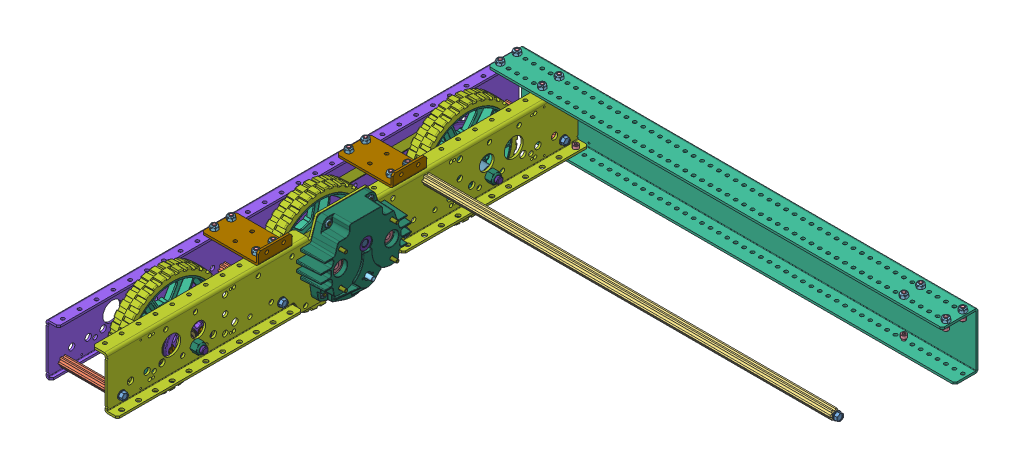
SolidWorks assembly AM14U3 Square Half, configuration Default. Lengths in mm.
Overall size (722.96 499.91 726.08).
151 component instances, 36 part files, 25 mates.
Components (placement in the parent):
- AM14U3 Square Frame Half-1: AM14U3 Square Frame Half [Default] at (326.068 37.2757 -291.2758) size (722.38 428.62 726.08)
  - 0.25-20 x 0.75 in Thread Rolling Screw-1: 0.25-20 x 0.75 in Thread Rolling Screw [FHTS 0.25-20-G-0.75-C] at (-600.075 -67.691 639.064) x (-1 0 0) z (0 0.924225 0.381849) size (24.64 12.19 12.19)
  - 0.25-20 x 0.75 in Thread Rolling Screw-4: 0.25-20 x 0.75 in Thread Rolling Screw [FHTS 0.25-20-G-0.75-C] at (-600.075 -67.691 -27.94) x (-1 0 0) z (0 0.924225 0.381849) size (24.64 12.19 12.19)
  - 0.25-20 x 0.75 in Thread Rolling Screw-5: 0.25-20 x 0.75 in Thread Rolling Screw [FHTS 0.25-20-G-0.75-C] at (-692.15 -67.691 -27.813) size (24.64 12.19 12.19)
  - 0.25-20 x 0.75 in Thread Rolling Screw-7: 0.25-20 x 0.75 in Thread Rolling Screw [FHTS 0.25-20-G-0.75-C] at (-603.25 -15.494 178.562) size (24.64 12.19 12.19)
  - 0.25-20 x 0.75 in Thread Rolling Screw-9: 0.25-20 x 0.75 in Thread Rolling Screw [FHTS 0.25-20-G-0.75-C] at (-692.15 -67.691 638.937) size (24.64 12.19 12.19)
  - 0.25-20 x 0.75 in Thread Rolling Screw-10: 0.25-20 x 0.75 in Thread Rolling Screw [FHTS 0.25-20-G-0.75-C] at (19.05 -15.494 178.562) x (-1 0 0) z (0 0.525103 -0.851039) size (24.64 12.19 12.19)
  - 500 Churro 3.375 in-1: 500 Churro 3.375 in [Default] at (-603.25 -67.691 -27.813) x (0 -0.866025 0.5) z (-1 0 0) size (14.66 12.7 85.72)
  - 500 Churro 3.375 in-2: 500 Churro 3.375 in [Default] at (-603.25 -67.691 638.937) x (0 -0.866025 0.5) z (-1 0 0) size (14.66 12.7 85.72)
  - 500 Churro 24.25 in-1: 500 Churro 24.25 in [Default] at (15.875 -15.494 178.562) x (0 0 -1) z (-1 0 0) size (14.66 12.7 615.95)
  - 10-32 x 0.5 in SHCS Screw-19: 10-32 x 0.5 in SHCS Screw [HX-SHCS 0.19-32x1.375x1-C] at (-679.45 -11.43 -11.938) x (0 1 0) z (0 0 1) size (17.53 7.94 7.94)
  - 10-32 x 0.5 in SHCS Screw-20: 10-32 x 0.5 in SHCS Screw [HX-SHCS 0.19-32x1.375x1-C] at (-679.45 -11.43 -37.338) x (0 1 0) z (0 0 1) size (17.53 7.94 7.94)
  - 10-32 x 0.5 in SHCS Screw-21: 10-32 x 0.5 in SHCS Screw [HX-SHCS 0.19-32x1.375x1-C] at (-615.95 -11.43 -37.338) x (0 1 0) z (0 0 1) size (17.53 7.94 7.94)
  - 10-32 x 0.5 in SHCS Screw-22: 10-32 x 0.5 in SHCS Screw [HX-SHCS 0.19-32x1.375x1-C] at (-615.95 -11.43 -11.938) x (0 1 0) z (0 0 1) size (17.53 7.94 7.94)
  - 10-32 x 0.5 in SHCS Screw-23: 10-32 x 0.5 in SHCS Screw [HX-SHCS 0.19-32x1.375x1-C] at (-590.55 -73.152 -37.338) x (0 -1 0) z (0 0 1) size (17.53 7.94 7.94)
  - 10-32 x 0.5 in SHCS Screw-24: 10-32 x 0.5 in SHCS Screw [HX-SHCS 0.19-32x1.375x1-C] at (-6.35 -11.176 -37.338) x (0 1 0) z (0.222581 0 0.974914) size (17.53 7.94 7.94)
  - 10-32 x 0.5 in SHCS Screw-25: 10-32 x 0.5 in SHCS Screw [HX-SHCS 0.19-32x1.375x1-C] at (-6.35 -11.176 -11.938) x (0 1 0) z (0.81526 0 0.579096) size (17.53 7.94 7.94)
  - 10-32 x 0.5 in SHCS Screw-26: 10-32 x 0.5 in SHCS Screw [HX-SHCS 0.19-32x1.375x1-C] at (-69.85 -11.176 -37.338) x (0 1 0) z (0 0 1) size (17.53 7.94 7.94)
  - 10-32 x 0.5 in SHCS Screw-27: 10-32 x 0.5 in SHCS Screw [HX-SHCS 0.19-32x1.375x1-C] at (-69.85 -11.176 -11.938) x (0 1 0) z (0.111454 0 0.99377) size (17.53 7.94 7.94)
  - 10-32 x 0.5 in SHCS Screw-28: 10-32 x 0.5 in SHCS Screw [HX-SHCS 0.19-32x1.375x1-C] at (-95.25 -73.406 -37.338) x (0 -1 0) z (0.007214 0 0.999974) size (17.53 7.94 7.94)
  - 10-32 Nylock Nut-19: 10-32 Nylock Nut [Default] at (-679.45 0 -11.938) x (1 0 0) z (0 1 0) size (10.18 11.01 7.1)
  - 10-32 Nylock Nut-21: 10-32 Nylock Nut [Default] at (-679.45 0 -37.338) x (1 0 0) z (0 1 0) size (10.18 11.01 7.1)
  - 10-32 Nylock Nut-22: 10-32 Nylock Nut [Default] at (-615.95 0 -11.938) x (1 0 0) z (0 1 0) size (10.18 11.01 7.1)
  - 10-32 Nylock Nut-23: 10-32 Nylock Nut [Default] at (-615.95 0 -37.338) x (1 0 0) z (0 1 0) size (10.18 11.01 7.1)
  - 10-32 Nylock Nut-25: 10-32 Nylock Nut [Default] at (-69.85 0 -11.938) x (1 0 0) z (0 1 0) size (10.18 11.01 7.1)
  - 10-32 Nylock Nut-26: 10-32 Nylock Nut [Default] at (-69.85 0 -37.338) x (1 0 0) z (0 1 0) size (10.18 11.01 7.1)
  - 10-32 Nylock Nut-27: 10-32 Nylock Nut [Default] at (-6.35 0 -11.938) x (1 0 0) z (0 1 0) size (10.18 11.01 7.1)
  - 10-32 Nylock Nut-28: 10-32 Nylock Nut [Default] at (-6.35 0 -37.338) x (1 0 0) z (0 1 0) size (10.18 11.01 7.1)
  - 10-32 Nylock Nut-29: 10-32 Nylock Nut [Default] at (-95.25 -84.582 -37.338) x (1 0 0) z (0 -1 0) size (10.18 11.01 7.1)
  - 10-32 Nylock Nut-30: 10-32 Nylock Nut [Default] at (-590.55 -84.582 -37.338) x (1 0 0) z (0 -1 0) size (10.18 11.01 7.1)
  - 10-32 x 0.5 in SHCS Screw-29: 10-32 x 0.5 in SHCS Screw [HX-SHCS 0.19-32x1.375x1-C] at (-679.45 -11.43 191.262) x (0 1 0) z (0 0 1) size (17.53 7.94 7.94)
  - 10-32 x 0.5 in SHCS Screw-30: 10-32 x 0.5 in SHCS Screw [HX-SHCS 0.19-32x1.375x1-C] at (-679.45 -11.43 216.662) x (0 1 0) z (0 0 1) size (17.53 7.94 7.94)
  - 10-32 x 0.5 in SHCS Screw-31: 10-32 x 0.5 in SHCS Screw [HX-SHCS 0.19-32x1.375x1-C] at (-615.95 -11.43 191.262) x (0 1 0) z (0 0 1) size (17.53 7.94 7.94)
  - 10-32 x 0.5 in SHCS Screw-32: 10-32 x 0.5 in SHCS Screw [HX-SHCS 0.19-32x1.375x1-C] at (-615.95 -11.43 216.662) x (0 1 0) z (0 0 1) size (17.53 7.94 7.94)
  - 10-32 x 0.5 in SHCS Screw-33: 10-32 x 0.5 in SHCS Screw [HX-SHCS 0.19-32x1.375x1-C] at (-615.95 -11.43 394.462) x (0 1 0) z (0 0 1) size (17.53 7.94 7.94)
  - 10-32 x 0.5 in SHCS Screw-34: 10-32 x 0.5 in SHCS Screw [HX-SHCS 0.19-32x1.375x1-C] at (-615.95 -11.43 419.862) x (0 1 0) z (0 0 1) size (17.53 7.94 7.94)
  - 10-32 x 0.5 in SHCS Screw-35: 10-32 x 0.5 in SHCS Screw [HX-SHCS 0.19-32x1.375x1-C] at (-679.45 -11.43 394.462) x (0 1 0) z (0 0 1) size (17.53 7.94 7.94)
  - 10-32 x 0.5 in SHCS Screw-36: 10-32 x 0.5 in SHCS Screw [HX-SHCS 0.19-32x1.375x1-C] at (-679.45 -11.43 419.862) x (0 1 0) z (0 0 1) size (17.53 7.94 7.94)
  - 10-32 Nylock Nut-31: 10-32 Nylock Nut [Default] at (-679.45 -0.254 419.862) x (1 0 0) z (0 1 0) size (10.18 11.01 7.1)
  - 10-32 Nylock Nut-32: 10-32 Nylock Nut [Default] at (-679.45 -0.254 394.462) x (1 0 0) z (0 1 0) size (10.18 11.01 7.1)
  - 10-32 Nylock Nut-33: 10-32 Nylock Nut [Default] at (-615.95 -0.254 394.462) x (1 0 0) z (0 1 0) size (10.18 11.01 7.1)
  - 10-32 Nylock Nut-34: 10-32 Nylock Nut [Default] at (-615.95 -0.254 419.862) x (1 0 0) z (0 1 0) size (10.18 11.01 7.1)
  - 10-32 Nylock Nut-35: 10-32 Nylock Nut [Default] at (-679.45 -0.254 216.662) x (1 0 0) z (0 1 0) size (10.18 11.01 7.1)
  - 10-32 Nylock Nut-37: 10-32 Nylock Nut [Default] at (-679.45 -0.254 191.262) x (1 0 0) z (0 1 0) size (10.18 11.01 7.1)
  - 10-32 Nylock Nut-38: 10-32 Nylock Nut [Default] at (-615.95 -0.254 216.662) x (1 0 0) z (0 1 0) size (10.18 11.01 7.1)
  - 10-32 Nylock Nut-39: 10-32 Nylock Nut [Default] at (-615.95 -0.254 191.262) x (1 0 0) z (0 1 0) size (10.18 11.01 7.1)
  - AM14U3 End Plate_Square-1: AM14U3 End Plate_Square [Default] at (-488.098 60.9785 -76.8664) x (1 0 0) z (0 -1 0) size (685.8 53.97 84.58)
  - AM14U3 Inner Plate_Square-1: AM14U3 Inner Plate_Square [Default] at (-612.1116 -19.2169 590.6409) x (0 0 -1) z (0 -1 0) size (711.2 38.1 116.33)
  - AM14U3 Outer Plate_Square-1: AM14U3 Outer Plate_Square [Default] at (-667.7485 -27.0221 21.6115) x (0 0 1) z (0 -1 0) size (711.2 19.05 77.72)
  - Bracket 2x3 Hole Pattern-1: Bracket 2x3 Hole Pattern [Default] at (-685.8 -3.429 445.262) size (85.72 19.05 50.8)
  - Bracket 2x3 Hole Pattern-2: Bracket 2x3 Hole Pattern [Default] at (-685.8 -3.429 242.062) size (85.72 19.05 50.8)
  - 500 Churro 3.375 in-5: 500 Churro 3.375 in [Default] at (-688.975 -66.929 397.637) x (0 0 -1) z (1 0 0) size (14.66 12.7 85.72)
  - 500 Churro 3.375 in-6: 500 Churro 3.375 in [Default] at (-688.975 -66.929 213.487) x (0 0 -1) z (1 0 0) size (14.66 12.7 85.72)
  - 0.25-20 x 0.75 in Thread Rolling Screw-11: 0.25-20 x 0.75 in Thread Rolling Screw [FHTS 0.25-20-G-0.75-C] at (-600.075 -66.929 397.637) x (-1 0 0) z (0 0.924225 0.381849) size (24.64 12.19 12.19)
  - 0.25-20 x 0.75 in Thread Rolling Screw-12: 0.25-20 x 0.75 in Thread Rolling Screw [FHTS 0.25-20-G-0.75-C] at (-600.075 -66.929 213.487) x (-1 0 0) z (0 0.924225 0.381849) size (24.64 12.19 12.19)
  - 0.25-20 x 0.75 in Thread Rolling Screw-13: 0.25-20 x 0.75 in Thread Rolling Screw [FHTS 0.25-20-G-0.75-C] at (-692.15 -66.929 397.637) size (24.64 12.19 12.19)
  - 0.25-20 x 0.75 in Thread Rolling Screw-14: 0.25-20 x 0.75 in Thread Rolling Screw [FHTS 0.25-20-G-0.75-C] at (-692.15 -66.929 213.487) size (24.64 12.19 12.19)
  - side-view-with-wheels-1: side-view-with-wheels [Default] x (0 0 -1) z (1 0 0) size (718.98 241.48 0)
- Toughbox Mini Kit 1 - Yellow-1: Toughbox Mini Kit 1 - Yellow [Default] at (-324.5487 -32.7384 105.387) x (0 0.001296 0.999999) z (-1 0 0) size (140.05 131.97 142.29)
  - TB Mini Small Hex Shaft-1: TB Mini Small Hex Shaft [Default] at (-128.9299 31.4042 -52.3959) x (-0.63944 -0.768841 0) z (-0.768841 0.63944 0) size (11 38.23 9.52)
  - Large Cluster Gear Hex 50t 0.375 in-1: Large Cluster Gear Hex 50t 0.375 in [Default] at (-91.0349 50.9043 -67.5597) x (-0.63944 -0.768841 0) z (0 0 -1) size (65.97 66.04 10.16)
  - Bearing FR6ZZ-1: Bearing FR6ZZ [Default] at (-96.247 60.278 -52.5991) x (-0.893862 0.448342 0) z (0 0 1) size (24.69 24.69 7.16)
  - 10-32 Nylock Nut-1: 10-32 Nylock Nut [Default] at (-129.8464 -8.0737 -56.3837) x (0.501678 0.865055 0) z (0 0 -1) size (10.18 11.01 7.1)
  - 10-32 Nylock Nut-2: 10-32 Nylock Nut [Default] at (-59.2462 80.7349 -56.3837) x (0.999999 -0.001296 0) z (0 0 -1) size (10.18 11.01 7.1)
  - 10-32 Nylock Nut-3: 10-32 Nylock Nut [Default] at (-122.7461 80.8172 -56.3837) x (0.500567 0.865698 0) z (0 0 -1) size (10.18 11.01 7.1)
  - 10-32 Nylock Nut-4: 10-32 Nylock Nut [Default] at (-52.3764 -8.1741 -56.3837) x (-0.501678 -0.865055 0) z (0 0 -1) size (10.18 11.01 7.1)
  - Washer 5-16 in-1: Washer 5-16 in [Default] at (-52.3162 38.3079 -77.7705) x (-0.418041 0.908428 0) z (0 0 -1) size (17.53 17.53 1.47)
  - Washer 5-16 in-2: Washer 5-16 in [Default] at (-52.3162 38.3079 -76.2973) x (0.897267 -0.441488 0) z (0 0 -1) size (17.53 17.53 1.47)
  - Washer 5-16 in-3: Washer 5-16 in [Default] at (-129.7861 38.4083 -77.7705) x (-0.990116 0.140253 0) z (0 0 1) size (17.53 17.53 1.47)
  - Washer 5-16 in-4: Washer 5-16 in [Default] at (-129.7861 38.4083 -79.2437) x (-0.681761 0.731575 0) z (0 0 1) size (17.53 17.53 1.47)
  - CIM Gear 14t 8 mm-1: CIM Gear 14t 8 mm [Default] at (-52.3162 38.3079 -63.5973) x (0.081921 0.996639 0) z (0 0 -1) size (20.03 20.32 12.7)
  - CIM Gear 14t 8 mm-2: CIM Gear 14t 8 mm [Default] at (-129.7861 38.4083 -63.5973) x (0.725998 0.687697 0) z (0 0 -1) size (20.03 20.32 12.7)
  - TB Mini Housing-1: TB Mini Housing [Default] at (-91.0876 10.1882 -86.3557) x (0.999999 -0.001296 0) z (0 0 1) size (139.9 118.55 41.54)
  - 10-32 x 0.625 in SHCS Screw-1: 10-32 x 0.625 in SHCS Screw [Default] at (-52.2832 63.7078 -74.4685) x (-0.564778 -0.825243 0) z (-0.825243 0.564778 0) size (7.82 20.65 7.82)
  - 10-32 x 0.625 in SHCS Screw-2: 10-32 x 0.625 in SHCS Screw [Default] at (-122.7461 80.8172 -42.5915) x (0.507484 -0.861661 0) z (-0.861661 -0.507484 0) size (7.82 20.65 7.82)
  - 10-32 x 0.625 in SHCS Screw-3: 10-32 x 0.625 in SHCS Screw [Default] at (-52.3764 -8.1741 -42.5915) x (0.507484 -0.861661 0) z (-0.861661 -0.507484 0) size (7.82 20.65 7.82)
  - 10-32 x 0.625 in SHCS Screw-4: 10-32 x 0.625 in SHCS Screw [Default] at (-129.8464 -8.0737 -42.5915) x (0.507484 -0.861661 0) z (-0.861661 -0.507484 0) size (7.82 20.65 7.82)
  - 10-32 x 0.625 in SHCS Screw-5: 10-32 x 0.625 in SHCS Screw [Default] at (-59.2462 80.7349 -42.5915) x (0.740711 -0.671824 0) z (-0.671824 -0.740711 0) size (7.82 20.65 7.82)
  - 10-32 x 0.625 in SHCS Screw-6: 10-32 x 0.625 in SHCS Screw [Default] at (-52.3491 12.9079 -74.4685) x (-0.564778 -0.825243 0) z (-0.825243 0.564778 0) size (7.82 20.65 7.82)
  - 10-32 x 0.625 in SHCS Screw-7: 10-32 x 0.625 in SHCS Screw [Default] at (-129.7532 63.8083 -74.4685) x (-0.966277 -0.257503 0) z (-0.257503 0.966277 0) size (7.82 20.65 7.82)
  - 10-32 x 0.625 in SHCS Screw-8: 10-32 x 0.625 in SHCS Screw [Default] at (-129.819 13.0083 -74.4685) x (-0.99652 0.083357 0) z (0.083357 0.99652 0) size (7.82 20.65 7.82)
  - Bearing R6ZZ-3: Bearing R6ZZ [Default] at (-91.0349 50.9043 -84.8317) x (0.958138 -0.286306 0) z (0 0 1) size (22.23 22.23 7.11)
  - Bearing R6ZZ-4: Bearing R6ZZ [Default] at (-91.0876 10.1882 -84.8317) x (-0.661529 0.74992 0) z (0 0 1) size (22.23 22.23 7.11)
  - Retaining Clip 8 mm-1: Retaining Clip 8 mm [Default] at (-129.7861 38.4083 -63.5973) x (0 0 1) z (-1 0 0) size (1.09 14.83 14.83)
  - Retaining Clip 8 mm-2: Retaining Clip 8 mm [Default] at (-52.3162 38.3079 -63.5973) x (0 0 1) z (-1 0 0) size (1.09 14.83 14.83)
  - External Klipring 0.5 in-1: External Klipring 0.5 in [Default] at (-91.0876 10.1882 -64.4355) x (0.996411 -0.084651 0) z (0 0 1) size (19.07 20.96 1.27)
  - Hex Bearing FR8ZZ-1: Hex Bearing FR8ZZ [Default] at (-91.0876 10.1882 -44.6717) x (0.206517 -0.978443 0) z (0 0 -1) size (31.12 31.12 7.93)
  - Small Cluster Gear Hex 16t 0.375 in-1: Small Cluster Gear Hex 16t 0.375 in [Default] at (-91.0349 50.9043 -67.5597) x (0 0 1) z (0.346116 -0.938192 0) size (15.19 22.57 22.57)
  - Large Output Gear Hex 48t 0.5 in-1: Large Output Gear Hex 48t 0.5 in [Default] at (-91.0876 10.1882 -63.1655) x (0 0 1) z (0.744098 0.668071 0) size (10.21 63.42 63.42)
  - TB Mini Hex Output Shaft-2: TB Mini Hex Output Shaft [Default] at (-99.4862 -30.7356 -52.3197) x (0.206517 -0.978443 0) z (-0.978443 -0.206517 0) size (14.66 142.29 12.7)
- Wheel HiGrip 6 in - Hub, Double Pulley-1: Wheel HiGrip 6 in - Hub, Double Pulley [Default] at (-288.1818 8.7668 164.0924) x (-1 0 0) z (0 -0.669035 -0.743231) size (81.42 152.4 152.4)
  - Wheel HiGrip 6 in-1: Wheel HiGrip 6 in [Default] at (83.7987 67.439 110.9939) size (35.05 152.4 152.4)
    - Wheel HiGrip 6 in_Wheel-1: Wheel HiGrip 6 in_Wheel [Default] at (-52.6446 9.4231 21.378) size (35.05 132.08 132.08)
    - Wheel HiGrip 6 in_Tread-1: Wheel HiGrip 6 in_Tread [Default] at (-65.3446 9.4231 21.378) x (0 0 -1) z (1 0 0) size (152.4 152.4 25.58)
  - Half Pulley 42t 5 mm HTD-1: Half Pulley 42t 5 mm HTD [Default] at (47.6006 76.862 132.3719) x (1 0 0) z (0 -0.5 0.866025) size (13 74.23 74.23)
  - Half Pulley 42t 5 mm HTD-2: Half Pulley 42t 5 mm HTD [Default] at (64.263 76.862 132.3719) x (-1 0 0) z (0 -0.499927 0.866067) size (13 74.23 74.23)
  - 10-24 x 1.25 in Thread Forming Screw-1: 10-24 x 1.25 in Thread Forming Screw [93882A213] at (63.247 76.8605 108.5602) x (0 0 -1) z (1 0 0) size (10.52 10.52 35.59)
  - 10-24 x 1.25 in Thread Forming Screw-2: 10-24 x 1.25 in Thread Forming Screw [93882A213] at (63.247 97.4833 120.4656) x (0 0 -1) z (1 0 0) size (10.52 10.52 35.59)
  - 10-24 x 1.25 in Thread Forming Screw-3: 10-24 x 1.25 in Thread Forming Screw [93882A213] at (63.247 56.2398 144.2799) x (0 0 -1) z (1 0 0) size (10.52 10.52 35.59)
  - 10-24 x 1.25 in Thread Forming Screw-4: 10-24 x 1.25 in Thread Forming Screw [93882A213] at (63.247 76.8625 156.1852) x (0 -0.95788 -0.287168) z (1 0 0) size (10.52 10.52 35.59)
  - 10-24 x 1.25 in Thread Forming Screw-5: 10-24 x 1.25 in Thread Forming Screw [93882A213] at (63.247 97.4843 144.2781) x (0 -0.868976 0.494854) z (1 0 0) size (10.52 10.52 35.59)
  - 10-24 x 1.25 in Thread Forming Screw-6: 10-24 x 1.25 in Thread Forming Screw [93882A213] at (63.247 56.2388 120.4674) x (0 -0.748729 -0.662876) z (1 0 0) size (10.52 10.52 35.59)
  - Half Pulley 42t 5 mm HTD-3: Half Pulley 42t 5 mm HTD [Default] at (-1.9548 76.8628 132.3714) x (1 0 0) z (0 -1 -0.000063) size (13 74.23 74.23)
  - Half Pulley 42t 5 mm HTD-4: Half Pulley 42t 5 mm HTD [Default] at (14.7076 76.8628 132.3714) x (-1 0 0) z (0 -1 0.000021) size (13 74.23 74.23)
  - Hex Hub 500 EX-1: Hex Hub 500 EX [Default] at (-8.3048 76.8628 132.3714) x (0 -0.866025 -0.5) z (0 -0.5 0.866025) size (55.37 25.4 51.33)
  - 10-24 x 1.25 in Thread Forming Screw-7: 10-24 x 1.25 in Thread Forming Screw [93882A213] at (-5.2568 97.485 120.4652) x (0 0 1) z (-1 0 0) size (10.52 10.52 35.59)
  - 10-24 x 1.25 in Thread Forming Screw-8: 10-24 x 1.25 in Thread Forming Screw [93882A213] at (-5.2568 76.8628 108.5589) x (0 0 1) z (-1 0 0) size (10.52 10.52 35.59)
  - 10-24 x 1.25 in Thread Forming Screw-9: 10-24 x 1.25 in Thread Forming Screw [93882A213] at (-5.2568 56.2406 120.4652) x (0 0 1) z (-1 0 0) size (10.52 10.52 35.59)
  - 10-24 x 1.25 in Thread Forming Screw-10: 10-24 x 1.25 in Thread Forming Screw [93882A213] at (-5.2568 97.485 144.2777) x (0 -0.99374 -0.111715) z (-1 0 0) size (10.52 10.52 35.59)
  - 10-24 x 1.25 in Thread Forming Screw-11: 10-24 x 1.25 in Thread Forming Screw [93882A213] at (-5.2568 56.2406 144.2777) x (0 -0.138911 0.990305) z (-1 0 0) size (10.52 10.52 35.59)
  - 10-24 x 1.25 in Thread Forming Screw-12: 10-24 x 1.25 in Thread Forming Screw [93882A213] at (-5.2568 76.8628 156.1839) x (0 -0.98811 -0.15375) z (-1 0 0) size (10.52 10.52 35.59)
  - Hex Spacer 0.57 in x 0.5 ID-1: Hex Spacer 0.57 in x 0.5 ID [Default] at (57.8495 76.862 132.3719) x (0 -0.866025 -0.5) z (0 -0.5 0.866025) size (28.55 14.48 28.55)
- Wheel HiGrip 6 in - Bearings, Pulleys, Spacers-1: Wheel HiGrip 6 in - Bearings, Pulleys, Spacers [Default] at (-351.6685 -97.7524 104.462) size (85.56 152.4 152.4)
  - Wheel HiGrip 6 in-1: Wheel HiGrip 6 in [Default] at (83.7987 67.439 110.9939) size (35.05 152.4 152.4)
    - Wheel HiGrip 6 in_Wheel-1: Wheel HiGrip 6 in_Wheel [Default] at (-52.6446 9.4231 21.378) size (35.05 132.08 132.08)
    - Wheel HiGrip 6 in_Tread-1: Wheel HiGrip 6 in_Tread [Default] at (-65.3446 9.4231 21.378) x (0 0 -1) z (1 0 0) size (152.4 152.4 25.58)
  - Half Pulley 42t 5 mm HTD-1: Half Pulley 42t 5 mm HTD [Default] at (47.6006 76.862 132.3719) x (1 0 0) z (0 -0.5 0.866025) size (13 74.23 74.23)
  - Half Pulley 42t 5 mm HTD-2: Half Pulley 42t 5 mm HTD [Default] at (64.263 76.862 132.3719) x (-1 0 0) z (0 -0.499927 0.866067) size (13 74.23 74.23)
  - Bearing 1614ZZ-1: Bearing 1614ZZ [Default] at (62.612 76.862 132.3719) x (0 -0.157148 -0.987575) z (-1 0 0) size (28.57 28.57 9.53)
  - Bearing 1614ZZ-2: Bearing 1614ZZ [Default] at (15.2791 76.862 132.3719) x (0 0 -1) z (1 0 0) size (28.57 28.57 9.53)
  - 10-24 x 1.25 in Thread Forming Screw-1: 10-24 x 1.25 in Thread Forming Screw [93882A213] at (63.247 76.8605 108.5602) x (0 0 -1) z (1 0 0) size (10.52 10.52 35.59)
  - 10-24 x 1.25 in Thread Forming Screw-2: 10-24 x 1.25 in Thread Forming Screw [93882A213] at (63.247 97.4833 120.4656) x (0 0 -1) z (1 0 0) size (10.52 10.52 35.59)
  - 10-24 x 1.25 in Thread Forming Screw-3: 10-24 x 1.25 in Thread Forming Screw [93882A213] at (63.247 56.2398 144.2799) x (0 0 -1) z (1 0 0) size (10.52 10.52 35.59)
  - 10-24 x 1.25 in Thread Forming Screw-4: 10-24 x 1.25 in Thread Forming Screw [93882A213] at (63.247 76.8625 156.1852) x (0 -0.95788 -0.287168) z (1 0 0) size (10.52 10.52 35.59)
  - 10-24 x 1.25 in Thread Forming Screw-5: 10-24 x 1.25 in Thread Forming Screw [93882A213] at (63.247 97.4843 144.2781) x (0 -0.868976 0.494854) z (1 0 0) size (10.52 10.52 35.59)
  - 10-24 x 1.25 in Thread Forming Screw-6: 10-24 x 1.25 in Thread Forming Screw [93882A213] at (63.247 56.2388 120.4674) x (0 -0.977348 -0.211637) z (1 0 0) size (10.52 10.52 35.59)
  - Spacer 0.28 in x 0.382 ID-1: Spacer 0.28 in x 0.382 ID [Default] at (74.4865 76.862 132.3719) x (0 -0.35357 0.935408) z (-1 0 0) size (13.16 13.16 7.11)
  - Spacer 0.85 in x 0.38 ID-1: Spacer 0.85 in x 0.38 ID [Default] at (-11.0734 76.862 132.3719) x (0 0 -1) z (1 0 0) size (19.05 19.05 21.59)
- Wheel HiGrip 6 in - Bearings, Pulleys, Spacers-2: Wheel HiGrip 6 in - Bearings, Pulleys, Spacers [Default] at (-288.2554 72.1013 -86.6776) x (-1 0 0) z (0 -0.924225 -0.381849) size (85.56 152.4 152.4)
  - Wheel HiGrip 6 in-1: Wheel HiGrip 6 in [Default] at (83.7987 67.439 110.9939) size (35.05 152.4 152.4)
    - Wheel HiGrip 6 in_Wheel-1: Wheel HiGrip 6 in_Wheel [Default] at (-52.6446 9.4231 21.378) size (35.05 132.08 132.08)
    - Wheel HiGrip 6 in_Tread-1: Wheel HiGrip 6 in_Tread [Default] at (-65.3446 9.4231 21.378) x (0 0 -1) z (1 0 0) size (152.4 152.4 25.58)
  - Half Pulley 42t 5 mm HTD-1: Half Pulley 42t 5 mm HTD [Default] at (47.6006 76.862 132.3719) x (1 0 0) z (0 -0.5 0.866025) size (13 74.23 74.23)
  - Half Pulley 42t 5 mm HTD-2: Half Pulley 42t 5 mm HTD [Default] at (64.263 76.862 132.3719) x (-1 0 0) z (0 -0.499927 0.866067) size (13 74.23 74.23)
  - Bearing 1614ZZ-1: Bearing 1614ZZ [Default] at (62.612 76.862 132.3719) x (0 -0.157148 -0.987575) z (-1 0 0) size (28.57 28.57 9.53)
  - Bearing 1614ZZ-2: Bearing 1614ZZ [Default] at (15.2791 76.862 132.3719) x (0 0 -1) z (1 0 0) size (28.57 28.57 9.53)
  - 10-24 x 1.25 in Thread Forming Screw-1: 10-24 x 1.25 in Thread Forming Screw [93882A213] at (63.247 76.8605 108.5602) x (0 0 -1) z (1 0 0) size (10.52 10.52 35.59)
  - 10-24 x 1.25 in Thread Forming Screw-2: 10-24 x 1.25 in Thread Forming Screw [93882A213] at (63.247 97.4833 120.4656) x (0 0 -1) z (1 0 0) size (10.52 10.52 35.59)
  - 10-24 x 1.25 in Thread Forming Screw-3: 10-24 x 1.25 in Thread Forming Screw [93882A213] at (63.247 56.2398 144.2799) x (0 0 -1) z (1 0 0) size (10.52 10.52 35.59)
  - 10-24 x 1.25 in Thread Forming Screw-4: 10-24 x 1.25 in Thread Forming Screw [93882A213] at (63.247 76.8625 156.1852) x (0 -0.95788 -0.287168) z (1 0 0) size (10.52 10.52 35.59)
  - 10-24 x 1.25 in Thread Forming Screw-5: 10-24 x 1.25 in Thread Forming Screw [93882A213] at (63.247 97.4843 144.2781) x (0 -0.868976 0.494854) z (1 0 0) size (10.52 10.52 35.59)
  - 10-24 x 1.25 in Thread Forming Screw-6: 10-24 x 1.25 in Thread Forming Screw [93882A213] at (63.247 56.2388 120.4674) x (0 -0.977348 -0.211637) z (1 0 0) size (10.52 10.52 35.59)
  - Spacer 0.28 in x 0.382 ID-1: Spacer 0.28 in x 0.382 ID [Default] at (74.4865 76.862 132.3719) x (0 -0.35357 0.935408) z (-1 0 0) size (13.16 13.16 7.11)
  - Spacer 0.85 in x 0.38 ID-1: Spacer 0.85 in x 0.38 ID [Default] at (-11.0734 76.862 132.3719) x (0 0 -1) z (1 0 0) size (19.05 19.05 21.59)
- Hex Bearing FR8ZZ-1: Hex Bearing FR8ZZ [Default] at (-369.3104 -22.6683 14.2862) x (0 0.309139 -0.951017) z (1 0 0) size (31.12 31.12 7.93)
- 0.375-16 Nylock Nut-1: 0.375-16 Nylock Nut [91831A127] at (-274.007 -20.8903 236.8339) x (0 -1 0) z (0 0 1) size (14.29 12 16.5)
- 0.375-16 Nylock Nut-2: 0.375-16 Nylock Nut [91831A127] at (-274.007 -20.8903 -208.2615) x (0 -1 0) z (0 0 1) size (14.29 12 16.5)
- Timing Belt HTD 15 mm_Square-1: Timing Belt HTD 15 mm_Square [Default] at (-289.0679 -20.8903 236.8339) x (0 -0.007989 -0.999968) z (-1 0 0) size (291.74 69.19 15)
- Timing Belt HTD 15 mm_Square-2: Timing Belt HTD 15 mm_Square [Default] at (-335.856 -20.8903 -208.2615) x (0 -0.007989 0.999968) z (-1 0 0) size (291.74 69.19 15)
- 0.375-16 x 4.25 in HHS Bolt-3: 0.375-16 x 4.25 in HHS Bolt [HFBOLT 0.375-16x2.5x1-C] at (-372.2542 -20.8903 236.8339) size (114.12 16.48 14.27)
- 0.375-16 x 4.25 in HHS Bolt-4: 0.375-16 x 4.25 in HHS Bolt [HFBOLT 0.375-16x2.5x1-C] at (-372.2542 -20.8903 -208.2615) size (114.12 16.48 14.27)
Mates (geometry in assembly coordinates):
- Concentric1: concentric anti-aligned: cylinder of AM14U3 Square Frame Half-1/AM14U3 Inner Plate_Square-1 through (-277.182 -22.6683 14.2862) axis (1 0 0) radius 14.2875; cylinder of Toughbox Mini Kit 1 - Yellow-1/Hex Bearing FR8ZZ-1 through (-271.9496 -22.6683 14.2862) axis (-1 0 0) radius 14.2875
- Parallel1: parallel: plane of AM14U3 Square Frame Half-1/AM14U3 Inner Plate_Square-1 through (-274.007 57.3417 -33.3388) normal (0 1 0); line of Toughbox Mini Kit 1 - Yellow-1/TB Mini Housing-1 through (-273.4813 56.8989 -17.4638) axis (0 0 1)
- Coincident2: coincident anti-aligned: plane of AM14U3 Square Frame Half-1/AM14U3 Inner Plate_Square-1 through (-274.007 29.9097 420.6862) normal (1 0 0); plane of Toughbox Mini Kit 1 - Yellow-1/TB Mini Housing-1 through (-274.007 -22.6683 14.2862) normal (-1 0 0)
- Concentric2: concentric anti-aligned: cylinder of AM14U3 Square Frame Half-1/AM14U3 Outer Plate_Square-1 through (-254.956 -20.8903 236.8339) axis (-1 0 0) radius 4.826; cylinder of Wheel HiGrip 6 in - Bearings, Pulleys, Spacers-1/Spacer 0.28 in x 0.382 ID-1 through (-284.294 -20.8903 236.8339) axis (1 0 0) radius 6.5786
- Coincident3: coincident anti-aligned: plane of AM14U3 Square Frame Half-1/AM14U3 Inner Plate_Square-1 through (-277.182 29.9097 420.6862) normal (-1 0 0); plane of Wheel HiGrip 6 in - Bearings, Pulleys, Spacers-1/Spacer 0.28 in x 0.382 ID-1 through (-277.182 -20.8903 236.8339) normal (1 0 0)
- Concentric3: concentric anti-aligned: cylinder of AM14U3 Square Frame Half-1/AM14U3 Inner Plate_Square-1 through (-296.232 -20.8903 -208.2615) axis (1 0 0) radius 4.826; cylinder of Wheel HiGrip 6 in - Bearings, Pulleys, Spacers-2/Spacer 0.28 in x 0.382 ID-1 through (-355.6299 -20.8903 -208.2615) axis (-1 0 0) radius 6.5786
- Coincident4: coincident anti-aligned: plane of AM14U3 Square Frame Half-1/AM14U3 Inner Plate_Square-1 through (-277.182 29.9097 420.6862) normal (-1 0 0); plane of Wheel HiGrip 6 in - Bearings, Pulleys, Spacers-2/Spacer 0.85 in x 0.38 ID-1 through (-277.182 -20.8903 -208.2615) normal (1 0 0)
- Concentric4: concentric anti-aligned: cylinder of Toughbox Mini Kit 1 - Yellow-1/Hex Bearing FR8ZZ-1 through (-271.9496 -22.6683 14.2862) axis (-1 0 0) radius 14.2875; cylinder of Wheel HiGrip 6 in - Hub, Double Pulley-1/Hex Spacer 0.57 in x 0.5 ID-1 through (-360.5093 -22.6683 14.2862) axis (1 0 0) radius 14.2748
- Parallel2: parallel anti-aligned: plane of Toughbox Mini Kit 1 - Yellow-1/TB Mini Hex Output Shaft-2 through (-246.829 -15.496 12.7626) normal (0 0.743231 -0.669035); plane of Wheel HiGrip 6 in - Hub, Double Pulley-1/Hex Hub 500 EX-1 through (-279.877 -15.4808 12.7594) normal (0 -0.743231 0.669035)
- Coincident6: coincident anti-aligned: plane of Toughbox Mini Kit 1 - Yellow-1/Hex Bearing FR8ZZ-1 through (-279.877 -22.6683 14.2862) normal (-1 0 0); plane of Wheel HiGrip 6 in - Hub, Double Pulley-1/Hex Hub 500 EX-1 through (-279.877 -22.6675 14.286) normal (1 0 0)
- Concentric51: concentric aligned: cylinder of AM14U3 Square Frame Half-1/AM14U3 Outer Plate_Square-1 through (-362.907 -22.6683 14.2862) axis (-1 0 0) radius 14.2875; cylinder of Hex Bearing FR8ZZ-1 through (-361.383 -22.6683 14.2862) axis (-1 0 0) radius 13.97
- Coincident71: coincident anti-aligned: plane of AM14U3 Square Frame Half-1/AM14U3 Outer Plate_Square-1 through (-362.907 29.9097 -392.1138) normal (1 0 0); plane of Hex Bearing FR8ZZ-1 through (-362.907 -18.3497 1.0005) normal (-1 0 0)
- Coincident8: coincident anti-aligned: plane of Toughbox Mini Kit 1 - Yellow-1/TB Mini Hex Output Shaft-2 through (-246.829 -15.496 12.7626) normal (0 0.743231 -0.669035); plane of Hex Bearing FR8ZZ-1 through (-361.383 -15.496 12.7626) normal (0 -0.743231 0.669035)
- Coincident11: coincident anti-aligned: plane of AM14U3 Square Frame Half-1/AM14U3 Inner Plate_Square-1 through (-274.007 29.9097 420.6862) normal (1 0 0); plane of 0.375-16 Nylock Nut-1 through (-274.007 -13.7466 224.4605) normal (-1 0 0)
- Coincident12: coincident anti-aligned: plane of AM14U3 Square Frame Half-1/AM14U3 Inner Plate_Square-1 through (-274.007 29.9097 420.6862) normal (1 0 0); plane of 0.375-16 Nylock Nut-2 through (-274.007 -13.7466 -220.6349) normal (-1 0 0)
- Concentric11: concentric anti-aligned: cylinder of Wheel HiGrip 6 in - Bearings, Pulleys, Spacers-1/Spacer 0.85 in x 0.38 ID-1 through (-341.1519 -20.8903 236.8339) axis (-1 0 0) radius 9.525; cylinder of Timing Belt HTD 15 mm_Square-1 through (-304.0679 -20.8903 236.8339) axis (1 0 0) radius 33.4264
- Concentric12: concentric anti-aligned: cylinder of Hex Bearing FR8ZZ-1 through (-361.383 -22.6683 14.2862) axis (-1 0 0) radius 14.2875; cylinder of Timing Belt HTD 15 mm_Square-1 through (-304.0679 -22.6683 14.2862) axis (1 0 0) radius 33.4264
- Coincident13: coincident anti-aligned: plane of Wheel HiGrip 6 in - Bearings, Pulleys, Spacers-1/Half Pulley 42t 5 mm HTD-1 through (-304.0679 -20.8903 236.8339) normal (1 0 0); plane of Timing Belt HTD 15 mm_Square-1 through (-304.0679 -20.8903 236.8339) normal (-1 0 0)
- Concentric13: concentric anti-aligned: cylinder of Hex Bearing FR8ZZ-1 through (-361.383 -22.6683 14.2862) axis (-1 0 0) radius 14.2875; cylinder of Timing Belt HTD 15 mm_Square-2 through (-350.856 -22.6683 14.2862) axis (1 0 0) radius 33.4264
- Concentric14: concentric aligned: cylinder of Wheel HiGrip 6 in - Bearings, Pulleys, Spacers-2/Spacer 0.85 in x 0.38 ID-1 through (-298.772 -20.8903 -208.2615) axis (1 0 0) radius 9.525; cylinder of Timing Belt HTD 15 mm_Square-2 through (-350.856 -20.8903 -208.2615) axis (1 0 0) radius 33.4264
- Coincident14: coincident anti-aligned: plane of Wheel HiGrip 6 in - Bearings, Pulleys, Spacers-2/Half Pulley 42t 5 mm HTD-1 through (-335.856 -20.8903 -208.2615) normal (-1 0 0); plane of Timing Belt HTD 15 mm_Square-2 through (-335.856 -20.8903 -208.2615) normal (1 0 0)
- Concentric72: concentric aligned: cylinder of AM14U3 Square Frame Half-1/AM14U3 Outer Plate_Square-1 through (-254.956 -20.8903 236.8339) axis (-1 0 0) radius 4.826; cylinder of 0.375-16 x 4.25 in HHS Bolt-3 through (-372.2542 -20.8903 236.8339) axis (-1 0 0) radius 4.7625
- Coincident102: coincident anti-aligned: plane of AM14U3 Square Frame Half-1/AM14U3 Outer Plate_Square-1 through (-366.082 29.9097 -392.1138) normal (-1 0 0); plane of 0.375-16 x 4.25 in HHS Bolt-3 through (-366.082 -12.6488 236.8339) normal (1 0 0)
- Concentric731: concentric aligned: cylinder of AM14U3 Square Frame Half-1/AM14U3 Outer Plate_Square-1 through (-254.956 -20.8903 -208.2615) axis (-1 0 0) radius 4.826; cylinder of 0.375-16 x 4.25 in HHS Bolt-4 through (-372.2542 -20.8903 -208.2615) axis (-1 0 0) radius 7.1374
- Coincident1031: coincident anti-aligned: plane of AM14U3 Square Frame Half-1/AM14U3 Outer Plate_Square-1 through (-366.082 29.9097 -392.1138) normal (-1 0 0); plane of 0.375-16 x 4.25 in HHS Bolt-4 through (-366.082 -12.6488 -208.2615) normal (1 0 0)
